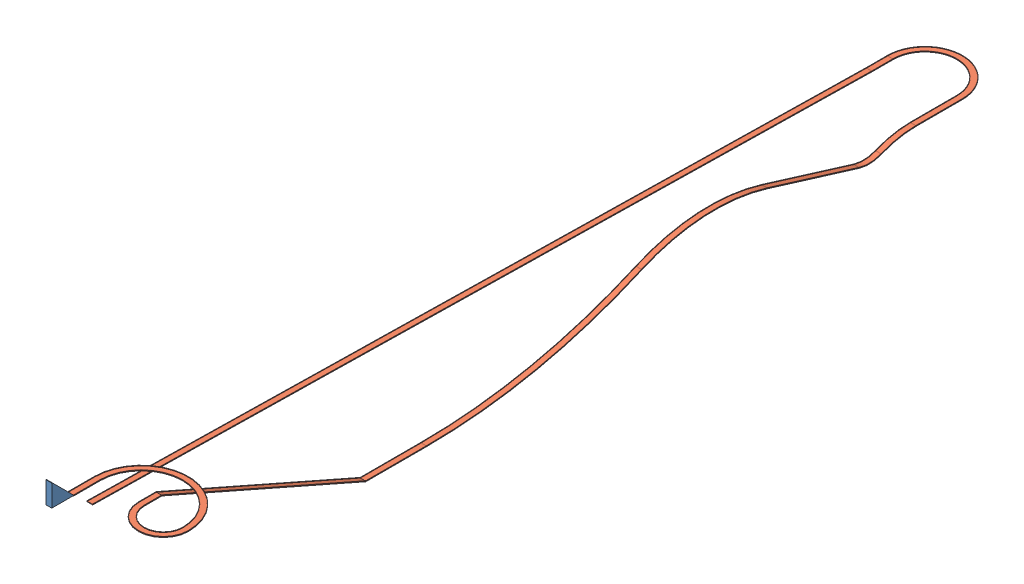
SolidWorks assembly track_bc604, configuration Default. Lengths in mm.
Overall size (13426.77 12644.92 101849.23).
2 component instances, 2 part files, 3 mates.
Components (placement in the parent):
- slope_45deg_2.5m_bc604-1: slope_45deg_2.5m_bc604 [Default] at (59.1199 603.2209 3085.997) size (650 2500 2500)
- extended_track_bc604-4: extended_track_bc604 [Default] at (-2068.6063 603.2209 636.0036) size (13426.77 10194.92 99399.23)
Mates (geometry in assembly coordinates):
- Coincident1: coincident: point of slope_45deg_2.5m_bc604-1; unknown of extended_track_bc604-4
- Parallel1: parallel anti-aligned: line of slope_45deg_2.5m_bc604-1 through (84.1199 603.2209 636.0036) axis (1 0 0); line of extended_track_bc604-4 through (684.1199 603.2209 636.0036) axis (-1 0 0)
- Parallel2: parallel anti-aligned: line of slope_45deg_2.5m_bc604-1 through (709.1199 603.2209 3085.997) axis (0 0 -1); line of extended_track_bc604-4 through (709.1199 553.2209 -2363.9964) axis (0 0 1)
